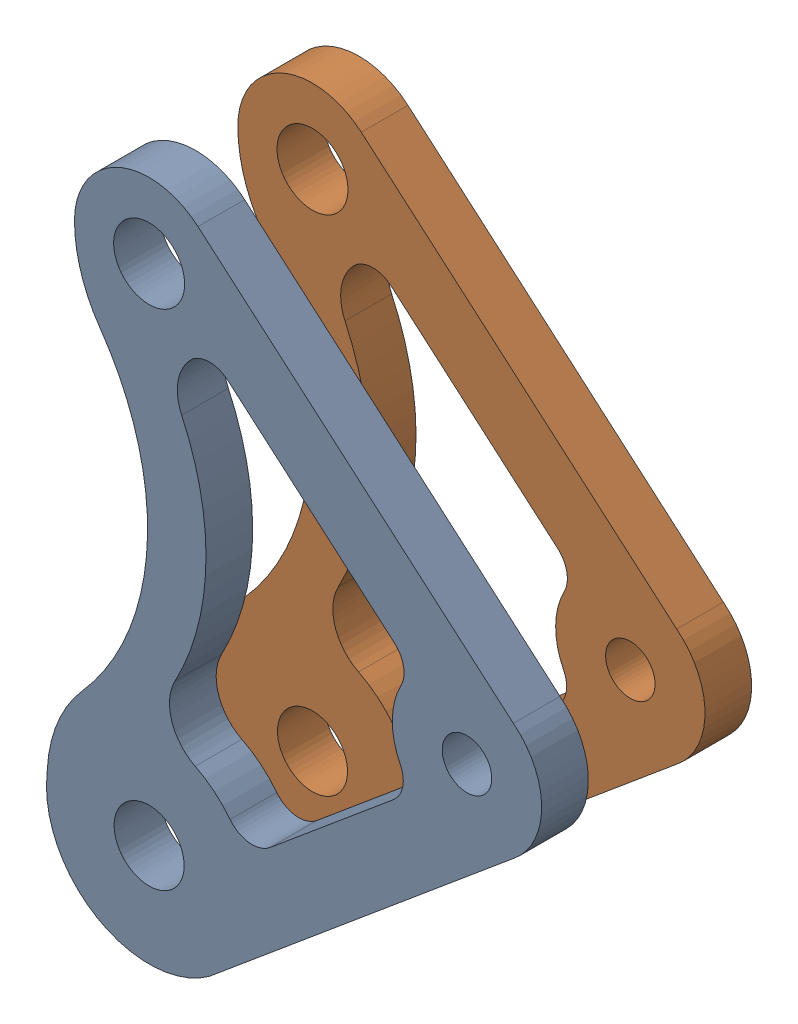
SolidWorks assembly SP-A0101-BB-Rear Rocker Assembly1, configuration Default. Lengths in mm.
Overall size (67.38 92.71 28.58).
3 component instances, 2 part files, 7 mates.
Components (placement in the parent):
- SP-20001-BB-Rear Rocker1-1: SP-20001-BB-Rear Rocker1 [Default] at (14.9343 -98.423 28.2147) size (67.38 92.71 6.35)
- SP-20001-BB-Rear Rocker1-2: SP-20001-BB-Rear Rocker1 [Default] at (14.9343 -98.423 5.9897) size (67.38 92.71 6.35)
- Part2^SP-A0101-BB-Rear Rocker Assembly1-1: Part2^SP-A0101-BB-Rear Rocker Assembly1 [Default] at (14.9343 -98.423 15.5147) (suppressed, hidden, virtual)
Mates (geometry in assembly coordinates):
- Distance1: distance = 15.875 mm anti-aligned: plane of SP-20001-BB-Rear Rocker-1 through (14.9343 -98.423 28.2147) normal (0 0 -1); plane of SP-20001-BB-Rear Rocker-2 through (14.9343 -98.423 12.3397) normal (0 0 1)
- Coincident2: coincident aligned: plane of SP-20001-BB-Rear Rocker-1 through (21.5757 -22.1543 34.5647) normal (0.653827 0.756644 0); plane of SP-20001-BB-Rear Rocker-2 through (21.5757 -22.1543 12.3397) normal (0.653827 0.756644 0)
- Coincident3: coincident aligned: plane of SP-20001-BB-Rear Rocker-1 through (64.49 -75.1673 34.5647) normal (0.641283 -0.767304 0); plane of SP-20001-BB-Rear Rocker-2 through (64.49 -75.1673 12.3397) normal (0.641283 -0.767304 0)
- InPlace1: in place: plane of ? through (14.9343 -98.423 15.5147) normal (0 0 1); plane of ? through (0 0 15.5147) normal (0 0 1); moOrthogonalPlaneRef_w of ? through (14.9343 -98.423 15.5147) normal (0 0 1); plane of ? through (0 0 15.5147) normal (0 1 0); plane of ? through (14.9343 -98.423 15.5147) normal (0 0 1); plane of ? through (0 0 15.5147) normal (1 0 0); plane of SP-20001-BB-Rear Rocker1-2 through (14.9343 -98.423 12.3397) normal (0 0 1); unknown of Part2^SP-A0101-BB-Rear Rocker Assembly1-1
- Coincident4: coincident aligned: plane of ?; plane of ?
- Coincident5: coincident aligned: moOrthogonalPlaneRef_w of SP-20001-BB-Rear Rocker-2 through (14.9343 -98.423 12.3397) normal (0 1 0); plane of Part2^SP-A0101-BB-Rear Rocker Assembly-1 through (14.9343 -98.423 15.5147) normal (0 1 0)
- Coincident6: coincident anti-aligned: moOrthogonalPlaneRef_w of SP-20001-BB-Rear Rocker-2 through (14.9343 -98.423 12.3397) normal (-1 0 0); plane of Part2^SP-A0101-BB-Rear Rocker Assembly-1 through (14.9343 -98.423 15.5147) normal (1 0 0)
